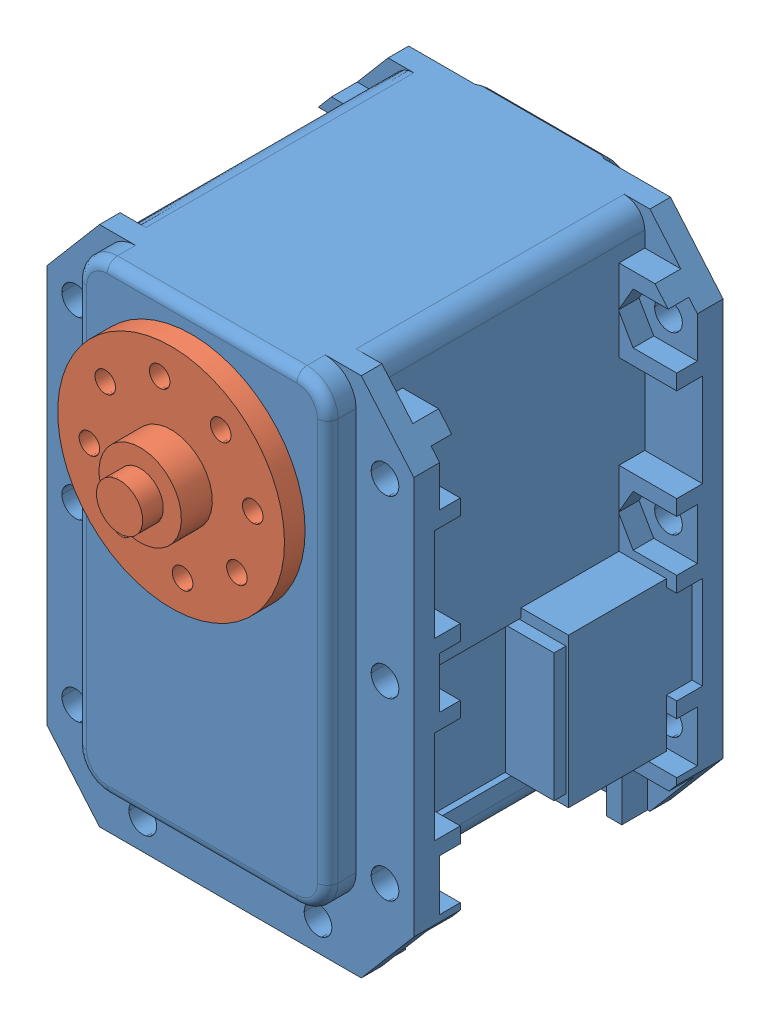
SolidWorks assembly MX-28, configuration Default. Lengths in mm.
Overall size (35.6 54.01 45).
2 component instances, 2 part files, 5 mates.
Components (placement in the parent):
- MX-28T_R.stp-1: MX-28T_R.stp [Default] at origin size (35.6 50.6 41.85)
- MX-28_horn-1: MX-28_horn [Default] at (0 0 18.75) x (0.798387 -0.602144 0) z (0 0 1) size (22 22 7)
Mates (geometry in assembly coordinates):
- Distance1: distance = 1 mm: plane of MX-28_horn-1 through (0 0 18.75) normal (0 0 -1); plane of MX-28T_R.stp-1 through (0 0 17.75) normal (0 0 1)
- Concentric2: concentric: cylinder of MX-28T_R.stp-1 through (0 0 17.75) axis (0 0 1) radius 2.85; cylinder of MX-28_horn-1 through (0 0 20.75) axis (0 0 -1) radius 11
- Coincident1: coincident: plane of MX-28T_R.stp-1 through (0 0 0) normal (0 0 1); plane of assembly through (0 0 0) normal (0 0 1)
- Coincident2: coincident: plane of MX-28T_R.stp-1 through (0 0 0) normal (0 1 0); plane of assembly through (0 0 0) normal (0 1 0)
- Coincident3: coincident: plane of MX-28T_R.stp-1 through (0 0 0) normal (1 0 0); plane of assembly through (0 0 0) normal (1 0 0)
